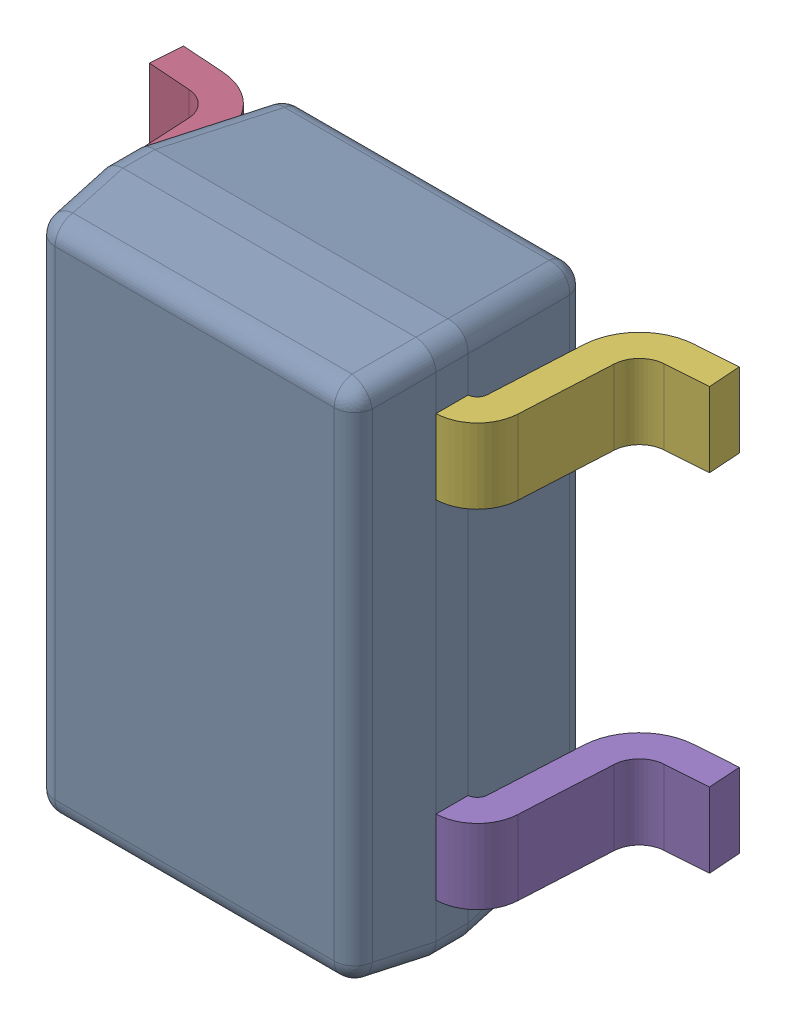
SolidWorks assembly DCK0005A, configuration ﾃﾞﾌｫﾙﾄ. Lengths in mm.
Overall size (2.1 2 1.01).
6 component instances, 2 part files, 0 mates.
Components (placement in the parent):
- BODY-SOT_2-1: BODY-SOT_2 [ﾃﾞﾌｫﾙﾄ] at (0 0 0.72) x (0 -1 0) z (-1 0 0) size (2 0.92 1.25)
- LEAD-SOT_2-1: LEAD-SOT_2 [ﾃﾞﾌｫﾙﾄ] at (-0.6816 -0.65 0.15) x (0 -1 0) z (-1 0 0) size (0.28 0.72 0.43)
- LEAD-SOT_2-2: LEAD-SOT_2 [ﾃﾞﾌｫﾙﾄ] at (-0.6816 0 0.15) x (0 -1 0) z (-1 0 0) size (0.28 0.72 0.43)
- LEAD-SOT_2-3: LEAD-SOT_2 [ﾃﾞﾌｫﾙﾄ] at (-0.6816 0.65 0.15) x (0 -1 0) z (-1 0 0) size (0.28 0.72 0.43)
- LEAD-SOT_2-4: LEAD-SOT_2 [ﾃﾞﾌｫﾙﾄ] at (0.6816 -0.65 0.15) x (0 1 0) z (1 0 0) size (0.28 0.72 0.43)
- LEAD-SOT_2-5: LEAD-SOT_2 [ﾃﾞﾌｫﾙﾄ] at (0.6816 0.65 0.15) x (0 1 0) z (1 0 0) size (0.28 0.72 0.43)
